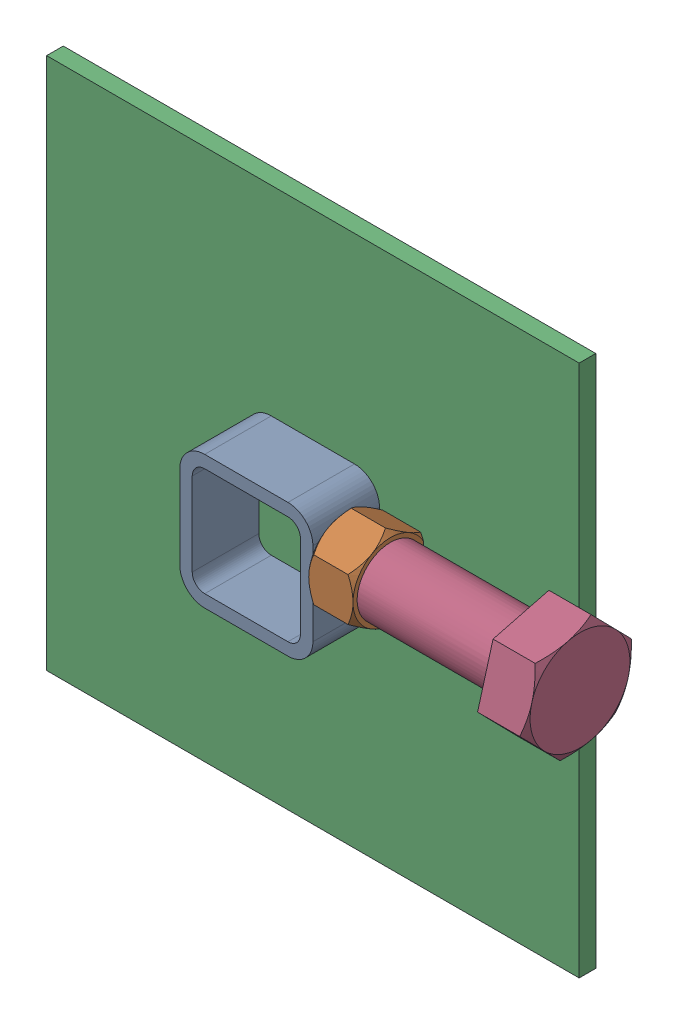
SolidWorks assembly 01-002-00-0(Default)-3, configuration Default. Lengths in mm.
Overall size (216.22 203.2 48.52).
5 component instances, 4 part files, 0 mates.
Components (placement in the parent):
- 01-005-00-0-7-1: 01-005-00-0-7 [Default] at origin size (67.69 50.8 28.57)
  - tube square_ai(PreviewCfg)-1: tube square_ai(PreviewCfg) [Default] at origin size (50.8 50.8 25.4)
  - hex nut_ai(HNUT 0.7500-10-D-C)-1: hex nut_ai(HNUT 0.7500-10-D-C) [Default] at (67.691 31.75 0) x (0 0 -1) z (1 0 0) size (28.57 33 16.89)
- 01-006-00-0-1: 01-006-00-0 [Default] at (-76.2 -76.2 -19.05) x (1 0 0) z (0 -1 0) size (203.2 6.35 203.2)
- hex bolt_ai(PreviewCfg)-1: hex bolt_ai(PreviewCfg) [Default] at (140.0175 31.75 0) x (-1 0 0) z (0 -0.268825 -0.963189) size (93.98 43.99 38.1)
